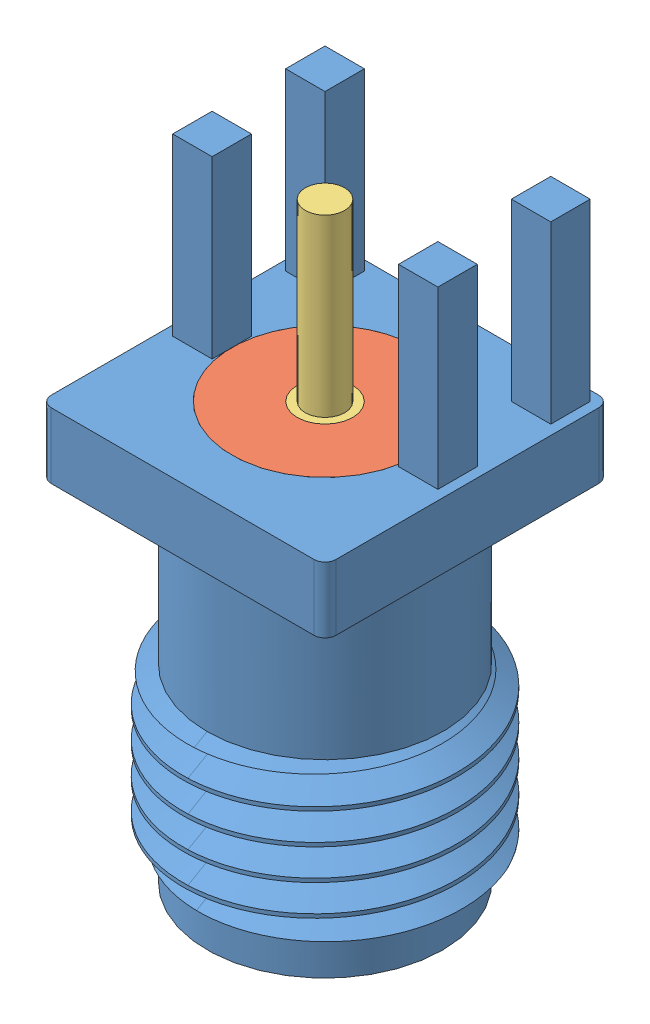
SolidWorks assembly SMA_female_edge_6.5x6.5, configuration Default. Lengths in mm.
Overall size (6.5 13.5 6.5).
3 component instances, 3 part files, 0 mates.
Components (placement in the parent):
- Body-1: Body [Default] at (0 -4 0.45) x (0 0 1) z (0 -1 0) size (6.5 6.5 13.5)
- Dielectric-1: Dielectric [Default] at (0 -4 0.45) x (0 0 1) z (0 -1 0) size (4.25 4.25 7.57)
- Pin-1: Pin [Default] at (0 -4 0.45) x (0 0 1) z (0 -1 0) size (1.27 1.27 11.57)
